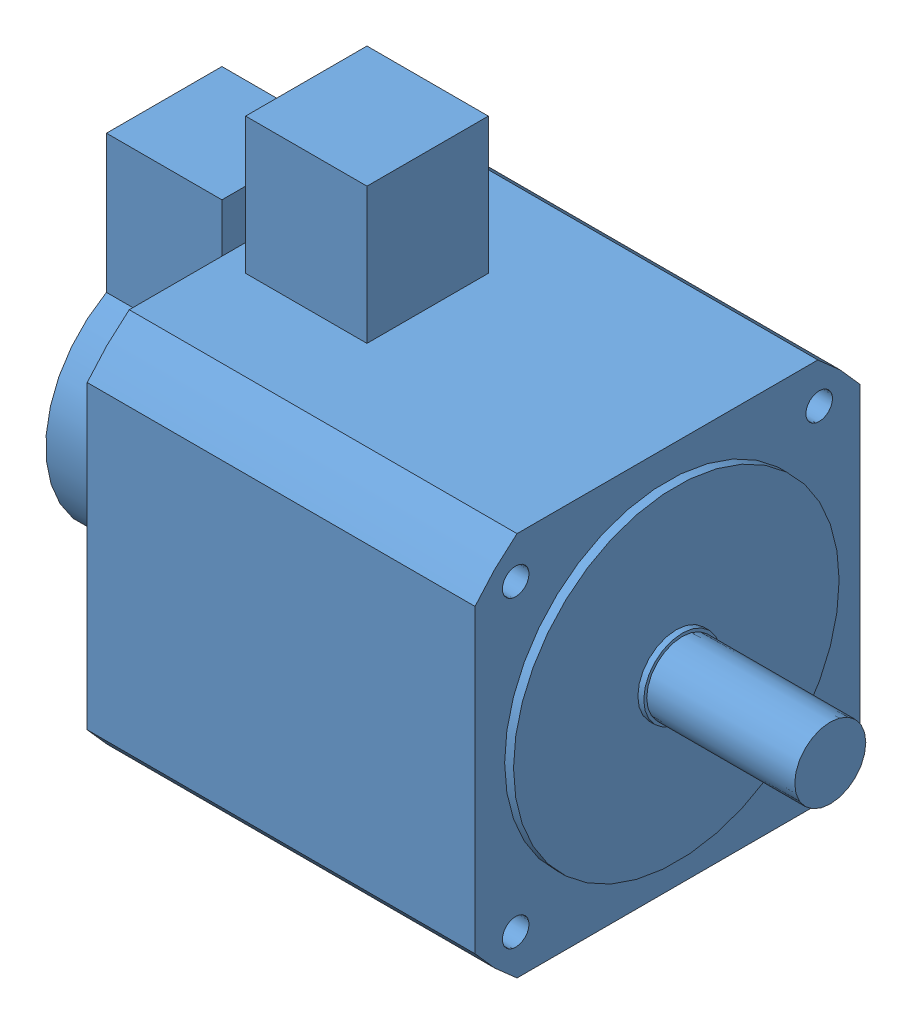
SolidWorks assembly assem WS120F - HC SFS152, configuration Default. Lengths in mm.
Overall size (429.7 193.51 173.52).
2 component instances, 2 part files, 4 mates.
Components (placement in the parent):
- WS120F grearbox-1: WS120F grearbox [Default] at origin size (259.7 165.02 173.52)
- HC SFS 152-2: HC SFS 152 [Default] at (-147.201 0 61) x (0 0 1) z (1 0 0) size (130 176 225)
Mates (geometry in assembly coordinates):
- Concentric4: concentric anti-aligned: cylinder of hop so WS120F-1 through (-160.201 0 61) axis (-1 0 0) radius 40; cylinder of HC SFS 152-2 through (-197.201 0 61) axis (1 0 0) radius 12
- Concentric5: concentric anti-aligned: cylinder of hop so WS120F-1 through (-202.201 51.2652 9.7348) axis (-1 0 0) radius 4; cylinder of HC SFS 152-2 through (-217.201 51.2652 9.7348) axis (1 0 0) radius 4.5
- Coincident2: coincident anti-aligned: plane of hop so WS120F-1 through (-202.201 65 126) normal (-1 0 0); plane of HC SFS 152-2 through (-202.201 0 61) normal (1 0 0)
- Coincident3: coordinate: point of hop so WS120F-1
